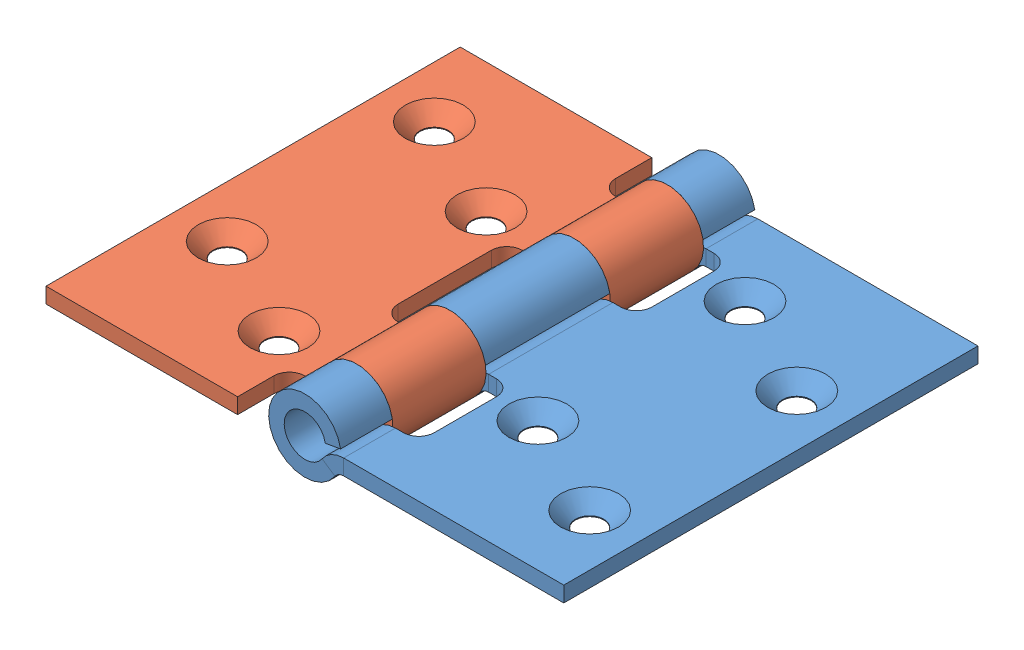
SolidWorks assembly 合页体, configuration 默认. Lengths in mm.
Overall size (100 14 80).
2 component instances, 3 part files, 4 mates.
Components (placement in the parent):
- 合页-1: 合页 [默认] at (-17.9542 -0.6061 40) size (57 14 80)
- 合页2-1: 合页2 [默认] at (-17.9542 -0.6061 120) size (54 14 80)
Mates (geometry in assembly coordinates):
- 在位1: in place: plane of 合页-1 through (-17.9542 -0.6061 120) normal (0 0 1); plane of ? through (0 0 120) normal (0 0 1); moOrthogonalPlaneRef_w of 合页-1 through (-17.9542 -0.6061 120) normal (0 0 1); plane of ? through (0 0 120) normal (0 1 0); plane of 合页-1 through (-17.9542 -0.6061 120) normal (0 0 1); plane of ? through (0 0 120) normal (1 0 0); plane of 合页-1 through (-17.9542 -0.6061 120) normal (0 0 1); unknown of 合页2-1
- 重合1: coincident aligned: plane of 合页-1; plane of 合页2-1
- 重合2: coincident aligned: moOrthogonalPlaneRef_w of 合页-1 through (-17.9542 -0.6061 120) normal (0 1 0); plane of 合页2-1 through (-17.9542 -0.6061 120) normal (0 1 0)
- 重合3: coincident anti-aligned: moOrthogonalPlaneRef_w of 合页-1 through (-17.9542 -0.6061 120) normal (-1 0 0); plane of 合页2-1 through (-17.9542 -0.6061 120) normal (1 0 0)
